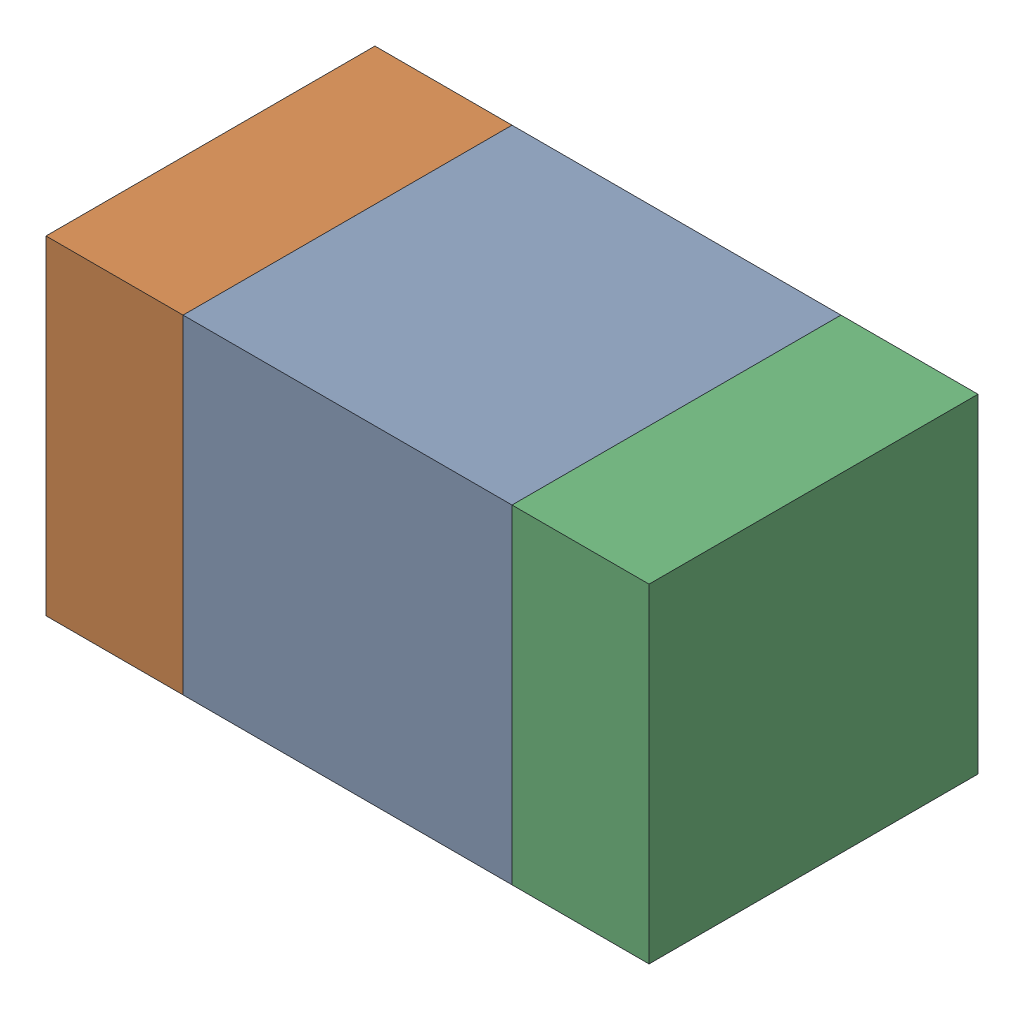
SolidWorks assembly C303_2PCB, configuration Default. Lengths in mm.
Overall size (1.1 0.6 0.6).
6 component instances, 2 part files, 0 mates.
Components (placement in the parent):
- 761606048-1: 761606048 [Default] at (141.1 97.8 0) size (0.6 0.6 0.6)
  - Extruded_9-1: Extruded_9 [Default] at origin size (0.6 0.6 0.6)
- 854785160-1: 854785160 [Default] at (140.675 97.8 0) size (0.25 0.6 0.6)
  - Extruded_19-1: Extruded_19 [Default] at origin size (0.25 0.6 0.6)
- 854785160-2: 854785160 [Default] at (141.525 97.8 0) size (0.25 0.6 0.6)
  - Extruded_19-1: Extruded_19 [Default] at origin size (0.25 0.6 0.6)
